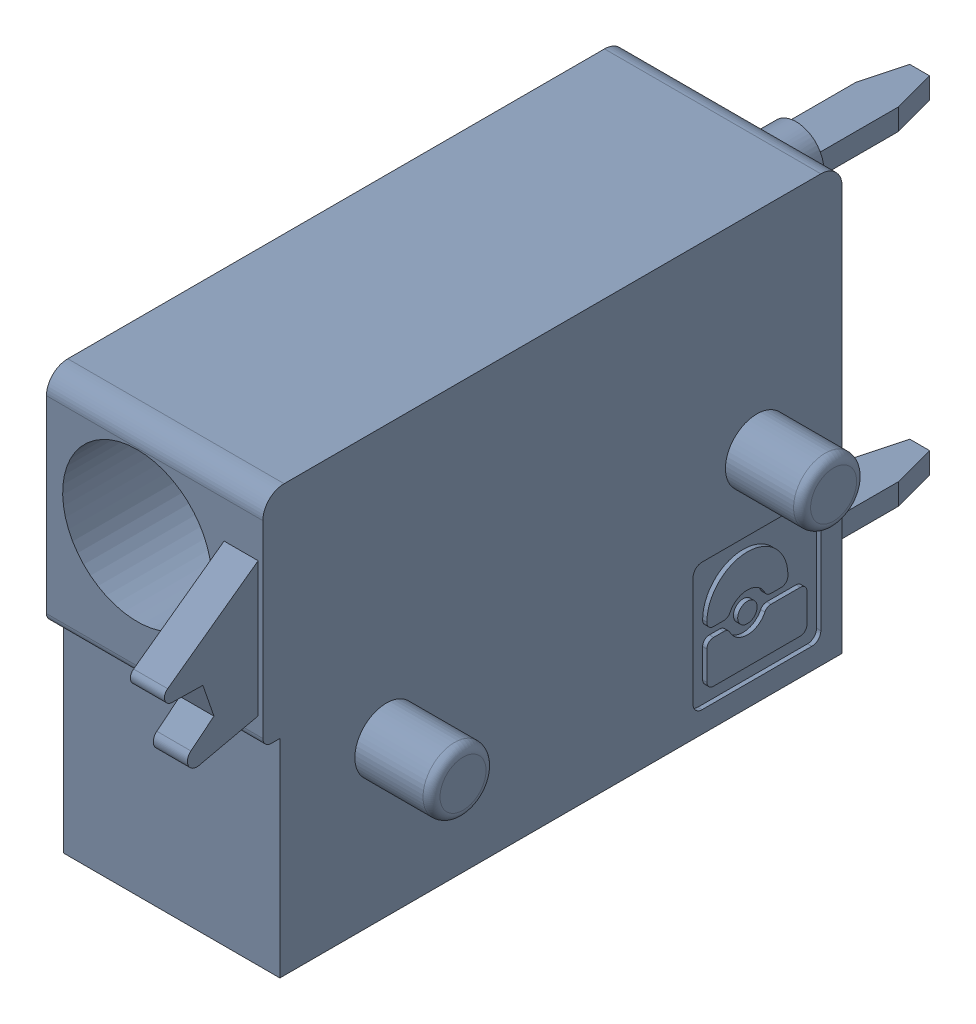
SolidWorks assembly J76, configuration Default. Lengths in mm.
Overall size (6.88 10 19.2).
2 component instances, 1 part files, 0 mates.
Components (placement in the parent):
- 1790348-1: 1790348 [Default] at (222.8851 -7.6199 0) x (0 1 0) z (1 0 0) size (10 19.2 6.88)
  - ffkds-v2-5.08-1: ffkds-v2-5.08 [Default] at (-23.7414 -38.158 -2.54) x (0 -1 0) z (0 0 1) size (19.2 10 6.88)
